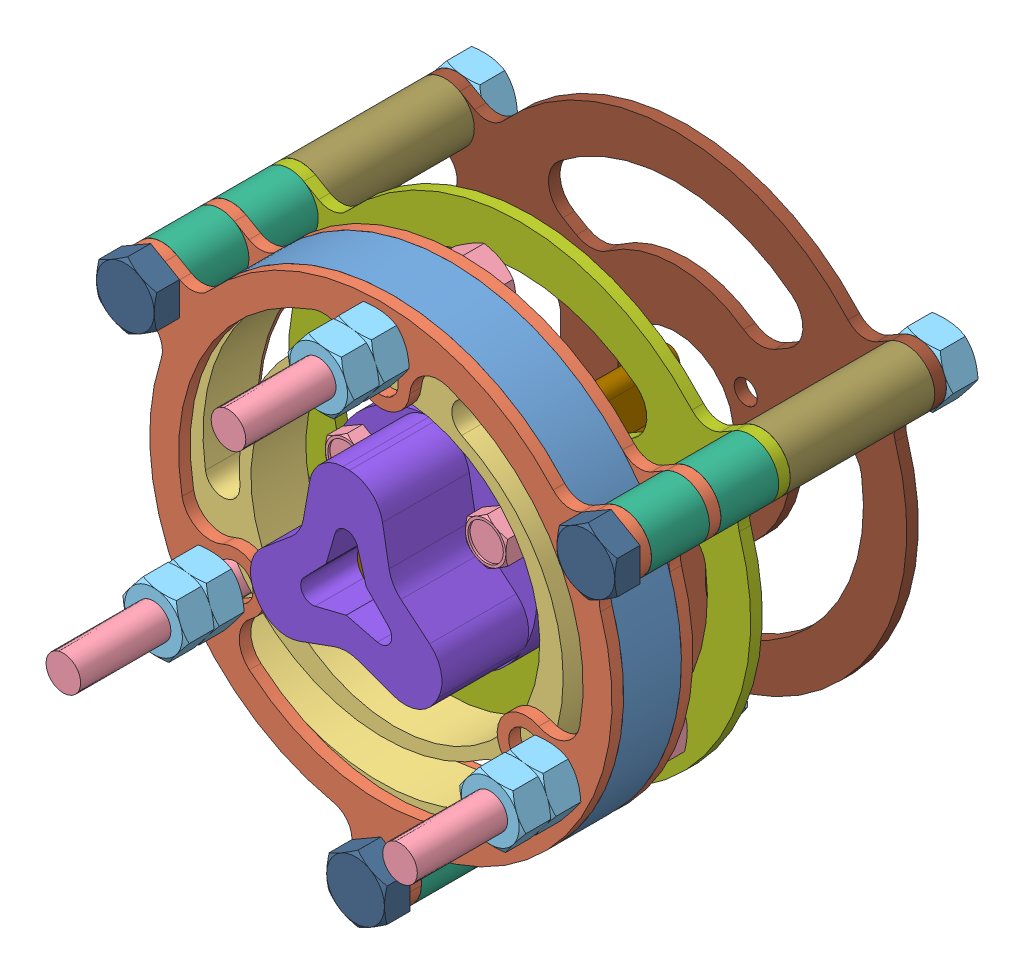
SolidWorks assembly Tri-Claw-Claw, configuration Default. Lengths in mm.
Overall size (123.65 123.16 86).
39 component instances, 13 part files, 77 mates.
Components (placement in the parent):
- ClawHousing-1: ClawHousing [Default] x (0.805239 -0.592951 0) z (0 0 1) size (80 80 10)
- ClawFrame-1: ClawFrame [Default] at (0 0 -2) x (0.866025 -0.5 0) z (0 0 1) size (91 89.67 2)
- ClawFrame-2: ClawFrame [Default] at (0 0 10) x (0.866025 -0.5 0) z (0 0 1) size (91 89.67 2)
- ClawCam-1: ClawCam [Default] x (-0.82094 -0.571014 0) z (0 0 1) size (76 76 9.5)
- hex screw_am-1: hex screw_am [B18.6.7M - M6 x 1.0 x 40 Indented HHMS --40N] at (-0.3706 33.6346 -6.7) x (0 0 1) z (-1 0 0) size (44.7 11.55 10)
- hex screw_am-2: hex screw_am [B18.6.7M - M6 x 1.0 x 40 Indented HHMS --40N] at (29.3137 -16.4964 -6.7) x (0 0 1) z (-1 0 0) size (44.7 11.55 10)
- hex screw_am-3: hex screw_am [B18.6.7M - M6 x 1.0 x 40 Indented HHMS --40N] at (-28.9431 -17.1383 -6.7) x (0 0 1) z (-1 0 0) size (44.7 11.55 10)
- hex nut style 1_am-1: hex nut style 1_am [B18.2.4.1M - Hex nut, Style 1,  M6 x 1 --D-N] at (-0.3706 33.6346 17.2) x (-0.923728 -0.383049 0) z (0 0 -1) size (10 11.55 5.2)
- hex nut style 1_am-2: hex nut style 1_am [B18.2.4.1M - Hex nut, Style 1,  M6 x 1 --D-N] at (29.3137 -16.4964 17.2) x (-0.923728 -0.383049 0) z (0 0 -1) size (10 11.55 5.2)
- hex nut style 1_am-3: hex nut style 1_am [B18.2.4.1M - Hex nut, Style 1,  M6 x 1 --D-N] at (-28.9431 -17.1383 17.2) x (-0.923728 -0.383049 0) z (0 0 -1) size (10 11.55 5.2)
- hex nut style 1_am-4: hex nut style 1_am [B18.2.4.1M - Hex nut, Style 1,  M6 x 1 --D-N] at (-0.3706 33.6346 12) x (-0.923728 -0.383049 0) z (0 0 -1) size (10 11.55 5.2)
- hex nut style 1_am-5: hex nut style 1_am [B18.2.4.1M - Hex nut, Style 1,  M6 x 1 --D-N] at (29.3137 -16.4964 12) x (-0.923728 -0.383049 0) z (0 0 -1) size (10 11.55 5.2)
- hex nut style 1_am-6: hex nut style 1_am [B18.2.4.1M - Hex nut, Style 1,  M6 x 1 --D-N] at (-28.9431 -17.1383 12) x (-0.923728 -0.383049 0) z (0 0 -1) size (10 11.55 5.2)
- ClawSpacer-1: ClawSpacer [Default] at (-39.8372 23 -2) x (-1 0 0) z (0 0 -1) size (10 10 10)
- ClawSpacer-2: ClawSpacer [Default] at (39.8372 23 -2) x (-1 0 0) z (0 0 -1) size (10 10 10)
- ClawSpacer-3: ClawSpacer [Default] at (0 -46 -2) x (-1 0 0) z (0 0 -1) size (10 10 10)
- ClawBackFrame-1: ClawBackFrame [Default] at (0 0 -14) x (0.866025 -0.5 0) z (0 0 1) size (91 89.67 2)
- Plate-TriStar-1: Plate-TriStar [Default] at (0 0 22.4) x (0.999374 -0.035386 0) z (0 0 1) size (60 60 1.5) (hidden)
- AlignmentToolHousing-1: AlignmentToolHousing [Default] at (0 0 -12) size (36 36 30)
- AlignmentTool-1: AlignmentTool [Default] at (0 0 12.2777) x (-1 0 0) z (0 0 -1) size (15.93 15.31 50)
- hex screw_am-4: hex screw_am [B18.6.7M - M4 x 0.7 x 25 Indented HHMS --25N] at (12.1244 7 6) x (0 0 -1) z (1 0 0) size (28 8.08 7)
- hex screw_am-5: hex screw_am [B18.6.7M - M4 x 0.7 x 25 Indented HHMS --25N] at (-12.1244 7 6) x (0 0 -1) z (1 0 0) size (28 8.08 7)
- hex screw_am-6: hex screw_am [B18.6.7M - M4 x 0.7 x 25 Indented HHMS --25N] at (0 -14 6) x (0 0 -1) z (1 0 0) size (28 8.08 7)
- ClawSpacer-4: ClawSpacer [Default] at (-39.8372 23 10) x (-1 0 0) z (0 0 -1) size (10 10 10)
- ClawSpacer-5: ClawSpacer [Default] at (39.8372 23 0) x (0.923728 0.383049 0) z (0 0 1) size (10 10 10)
- ClawSpacer-6: ClawSpacer [Default] at (0 -46 10) x (-1 0 0) z (0 0 -1) size (10 10 10)
- hex nut style 1_am-10: hex nut style 1_am [B18.2.4.1M - Hex nut, Style 1,  M4 x 0.7 --D-N] at (-12.1244 7 -17.2) x (0.923728 0.383049 0) z (0 0 -1) size (7 8.08 3.2)
- hex nut style 1_am-11: hex nut style 1_am [B18.2.4.1M - Hex nut, Style 1,  M4 x 0.7 --D-N] at (12.1244 7 -17.2) x (0.923728 0.383049 0) z (0 0 -1) size (7 8.08 3.2)
- hex nut style 1_am-12: hex nut style 1_am [B18.2.4.1M - Hex nut, Style 1,  M4 x 0.7 --D-N] at (0 -14 -17.2) x (0.925899 0.377771 0) z (0 0 -1) size (7 8.08 3.2)
- hex bolt_am-1: hex bolt_am [B18.2.3.5M - Hex bolt M6 x 1.0 x 60 --18N] at (39.8372 23 16.38) x (0 0 -1) z (1 0 0) size (64.38 11.55 10)
- hex bolt_am-2: hex bolt_am [B18.2.3.5M - Hex bolt M6 x 1.0 x 60 --18N] at (0 -46 16.38) x (0 0 -1) z (1 0 0) size (64.38 11.55 10)
- hex bolt_am-3: hex bolt_am [B18.2.3.5M - Hex bolt M6 x 1.0 x 60 --18N] at (-39.8372 23 16.38) x (0 0 -1) z (1 0 0) size (64.38 11.55 10)
- ClawBackFrameMount-1: ClawBackFrameMount [Default] at (0 0 -41) x (0.866025 -0.5 0) z (0 0 1) size (91 89.67 2)
- ClawSpacerLong-1: ClawSpacerLong [Default] at (-39.8372 23 -14) x (-1 0 0) z (0 0 -1) size (10 10 25)
- ClawSpacerLong-2: ClawSpacerLong [Default] at (0 -46 -14) x (-1 0 0) z (0 0 -1) size (10 10 25)
- ClawSpacerLong-3: ClawSpacerLong [Default] at (39.8372 23 -14) x (-1 0 0) z (0 0 -1) size (10 10 25)
- hex nut style 1_am-13: hex nut style 1_am [B18.2.4.1M - Hex nut, Style 1,  M6 x 1 --D-N] at (0 -46 -46.2) x (0.923728 0.383049 0) z (0 0 -1) size (10 11.55 5.2)
- hex nut style 1_am-14: hex nut style 1_am [B18.2.4.1M - Hex nut, Style 1,  M6 x 1 --D-N] at (39.8372 23 -46.2) x (0.923728 0.383049 0) z (0 0 -1) size (10 11.55 5.2)
- hex nut style 1_am-15: hex nut style 1_am [B18.2.4.1M - Hex nut, Style 1,  M6 x 1 --D-N] at (-39.8372 23 -46.2) x (0.923728 0.383049 0) z (0 0 -1) size (10 11.55 5.2)
Mates (geometry in assembly coordinates):
- Coincident1: coincident: plane of ClawHousing-1 through (0 0 0) normal (0 0 -1); plane of ClawFrame-1 through (0 0 0) normal (0 0 1)
- Concentric1: concentric: cylinder of ClawHousing-1 through (0 0 10) axis (0 0 -1) radius 40; cylinder of ClawFrame-1 through (0 0 0) axis (0 0 -1) radius 40
- Concentric2: concentric: cylinder of ClawHousing-1 through (0 0 10) axis (0 0 -1) radius 40; cylinder of ClawFrame-2 through (0 0 12) axis (0 0 -1) radius 40
- Coincident2: coincident: plane of ClawHousing-1 through (0 0 10) normal (0 0 1); plane of ClawFrame-2 through (0 0 10) normal (0 0 -1)
- Concentric4: concentric: cylinder of ClawHousing-1 through (0 0 10) axis (0 0 -1) radius 40; cylinder of ClawCam-1 through (0 0 9.5) axis (0 0 -1) radius 38
- Concentric25: concentric: cylinder of ClawHousing-1 through (0 0 10) axis (0 0 -1) radius 40; cylinder of Plate-TriStar-1 through (0 0 23.9) axis (0 0 -1) radius 30
- Concentric3: concentric: cylinder of ClawFrame-1 through (25.1147 -14.5 0) axis (0 0 -1) radius 3; cylinder of ClawFrame-2 through (25.1147 -14.5 12) axis (0 0 -1) radius 3
- Coincident7: coincident: plane of ClawFrame-1 through (0 0 0) normal (0 0 1); plane of ClawCam-1 through (0 0 0) normal (0 0 -1)
- Concentric20: concentric: cylinder of ClawFrame-1 through (-39.8372 23 0) axis (0 0 -1) radius 3; cylinder of ClawSpacer-1 through (-39.8372 23 -12) axis (0 0 1) radius 3
- Coincident19: coincident: plane of ClawFrame-1 through (0 0 -2) normal (0 0 -1); plane of ClawSpacer-1 through (-39.8372 23 -2) normal (0 0 1)
- Concentric21: concentric: cylinder of ClawFrame-1 through (39.8372 23 0) axis (0 0 -1) radius 3; cylinder of ClawSpacer-2 through (39.8372 23 -12) axis (0 0 1) radius 3
- Coincident20: coincident: plane of ClawFrame-1 through (0 0 -2) normal (0 0 -1); plane of ClawSpacer-2 through (39.8372 23 -2) normal (0 0 1)
- Concentric22: concentric: cylinder of ClawFrame-1 through (0 -46 0) axis (0 0 -1) radius 3; cylinder of ClawSpacer-3 through (0 -46 -12) axis (0 0 1) radius 3
- Coincident21: coincident: plane of ClawFrame-1 through (0 0 -2) normal (0 0 -1); plane of ClawSpacer-3 through (0 -46 -2) normal (0 0 1)
- Concentric37: concentric: cylinder of ClawFrame-1 through (-39.8372 23 0) axis (0 0 -1) radius 3; cylinder of ClawSpacer-4 through (-39.8372 23 0) axis (0 0 1) radius 3
- Coincident33: coincident: plane of ClawFrame-1 through (0 0 0) normal (0 0 1); plane of ClawSpacer-5 through (39.8372 23 0) normal (0 0 -1)
- Coincident13: coincident: plane of ClawFrame-2 through (0 0 12) normal (0 0 1); plane of hex nut style 1_am-4 through (-2.5821 38.9678 12) normal (0 0 -1)
- Coincident15: coincident: plane of ClawFrame-2 through (0 0 12) normal (0 0 1); plane of hex nut style 1_am-5 through (27.1022 -11.1632 12) normal (0 0 -1)
- Coincident17: coincident: plane of ClawFrame-2 through (0 0 12) normal (0 0 1); plane of hex nut style 1_am-6 through (-31.1547 -11.8051 12) normal (0 0 -1)
- Coincident32: coincident: plane of ClawFrame-2 through (0 0 10) normal (0 0 -1); plane of ClawSpacer-4 through (-39.8372 23 10) normal (0 0 1)
- Concentric39: concentric: cylinder of ClawFrame-2 through (39.8372 23 12) axis (0 0 -1) radius 3; cylinder of ClawSpacer-5 through (39.8372 23 10) axis (0 0 -1) radius 3
- Coincident34: coincident: plane of ClawFrame-2 through (0 0 10) normal (0 0 -1); plane of ClawSpacer-6 through (0 -46 10) normal (0 0 1)
- Concentric40: concentric: cylinder of ClawFrame-2 through (0 -46 12) axis (0 0 -1) radius 3; cylinder of ClawSpacer-6 through (0 -46 0) axis (0 0 1) radius 3
- CamMateTangent2: cam tangent: cylinder of ClawCam-1 through (3.5524 0.2996 9.5) axis (0 0 -1) radius 30.5651; cylinder of hex screw_am-1 through (-0.3706 33.6346 -32.1) axis (0 0 -1) radius 3
- CamMateTangent3: cam tangent: cylinder of ClawCam-1 through (-2.0357 2.9267 9.5) axis (0 0 -1) radius 30.5651; cylinder of hex screw_am-3 through (-28.9431 -17.1383 -32.1) axis (0 0 -1) radius 3
- CamMateTangent4: cam tangent: cylinder of ClawCam-1 through (-1.5167 -3.2263 9.5) axis (0 0 -1) radius 30.5651; cylinder of hex screw_am-2 through (29.3137 -16.4964 -32.1) axis (0 0 -1) radius 3
- Concentric12: concentric: cylinder of hex screw_am-1 through (-0.3706 33.6346 -32.1) axis (0 0 -1) radius 3; cylinder of hex nut style 1_am-1 through (-0.3706 33.6346 42.2375) axis (0 0 -1) radius 3
- Concentric15: concentric: cylinder of hex screw_am-1 through (-0.3706 33.6346 -32.1) axis (0 0 -1) radius 3; cylinder of hex nut style 1_am-4 through (-0.3706 33.6346 37.0375) axis (0 0 -1) radius 3
- Concentric13: concentric: cylinder of hex screw_am-2 through (29.3137 -16.4964 -32.1) axis (0 0 -1) radius 3; cylinder of hex nut style 1_am-2 through (29.3137 -16.4964 42.2375) axis (0 0 -1) radius 3
- Concentric16: concentric: cylinder of hex screw_am-2 through (29.3137 -16.4964 -32.1) axis (0 0 -1) radius 3; cylinder of hex nut style 1_am-5 through (29.3137 -16.4964 37.0375) axis (0 0 -1) radius 3
- Concentric14: concentric: cylinder of hex screw_am-3 through (-28.9431 -17.1383 -32.1) axis (0 0 -1) radius 3; cylinder of hex nut style 1_am-3 through (-28.9431 -17.1383 42.2375) axis (0 0 -1) radius 3
- Concentric17: concentric: cylinder of hex screw_am-3 through (-28.9431 -17.1383 -32.1) axis (0 0 -1) radius 3; cylinder of hex nut style 1_am-6 through (-28.9431 -17.1383 37.0375) axis (0 0 -1) radius 3
- Coincident14: coincident: plane of hex nut style 1_am-1 through (-2.5821 38.9678 17.2) normal (0 0 -1); plane of hex nut style 1_am-4 through (-2.5821 38.9678 17.2) normal (0 0 1)
- Coincident23: coincident: plane of hex nut style 1_am-1 through (-2.5821 38.9678 22.4) normal (0 0 1); plane of Plate-TriStar-1 through (0 0 22.4) normal (0 0 -1)
- Coincident16: coincident: plane of hex nut style 1_am-2 through (27.1022 -11.1632 17.2) normal (0 0 -1); plane of hex nut style 1_am-5 through (27.1022 -11.1632 17.2) normal (0 0 1)
- Coincident18: coincident: plane of hex nut style 1_am-3 through (-31.1547 -11.8051 17.2) normal (0 0 -1); plane of hex nut style 1_am-6 through (-31.1547 -11.8051 17.2) normal (0 0 1)
- Concentric24: concentric: cylinder of ClawSpacer-1 through (-39.8372 23 -12) axis (0 0 1) radius 3; cylinder of ClawBackFrame-1 through (-39.8372 23 -12) axis (0 0 -1) radius 3
- Coincident22: coincident: plane of ClawSpacer-1 through (-39.8372 23 -12) normal (0 0 -1); plane of ClawBackFrame-1 through (0 0 -12) normal (0 0 1)
- Concentric23: concentric: cylinder of ClawSpacer-2 through (39.8372 23 -12) axis (0 0 1) radius 3; cylinder of ClawBackFrame-1 through (39.8372 23 -12) axis (0 0 -1) radius 3
- Coincident24: coincident: plane of ClawBackFrame-1 through (0 0 -12) normal (0 0 1); plane of AlignmentToolHousing-1 through (0 0 -12) normal (0 0 -1)
- Concentric26: concentric: cylinder of ClawBackFrame-1 through (-12.1244 7 -6) axis (0 0 -1) radius 2; cylinder of AlignmentToolHousing-1 through (-12.1244 7 28) axis (0 0 -1) radius 2
- Concentric27: concentric: cylinder of ClawBackFrame-1 through (0 -14 -6) axis (0 0 -1) radius 2; cylinder of AlignmentToolHousing-1 through (0 -14 28) axis (0 0 -1) radius 2
- Coincident42: coincident: plane of ClawBackFrame-1 through (0 0 -14) normal (0 0 -1); plane of hex nut style 1_am-10 through (-10.5763 3.2668 -14) normal (0 0 1)
- Coincident43: coincident: plane of ClawBackFrame-1 through (0 0 -14) normal (0 0 -1); plane of hex nut style 1_am-11 through (13.6724 3.2668 -14) normal (0 0 1)
- Coincident44: coincident: plane of ClawBackFrame-1 through (0 0 -14) normal (0 0 -1); plane of hex nut style 1_am-12 through (1.5267 -17.742 -14) normal (0 0 1)
- Concentric28: concentric: cylinder of AlignmentToolHousing-1 through (0 6.7889 -12) axis (0 0 -1) radius 2; cylinder of AlignmentTool-1 through (0 6.7889 -37.7223) axis (0 0 1) radius 2
- Concentric29: concentric: cylinder of AlignmentToolHousing-1 through (5.8794 -3.3944 -12) axis (0 0 1) radius 2; cylinder of AlignmentTool-1 through (5.8794 -3.3944 -37.7223) axis (0 0 -1) radius 2
- Concentric31: concentric: cylinder of AlignmentToolHousing-1 through (12.1244 7 28) axis (0 0 -1) radius 2; cylinder of hex screw_am-4 through (12.1244 7 31.4) axis (0 0 1) radius 2
- Coincident26: coincident: plane of AlignmentToolHousing-1 through (0 0 3) normal (0 0 1); plane of hex screw_am-4 through (12.1244 9 3) normal (0 0 -1)
- Concentric32: concentric: cylinder of AlignmentToolHousing-1 through (-12.1244 7 28) axis (0 0 -1) radius 2; cylinder of hex screw_am-5 through (-12.1244 7 31.4) axis (0 0 1) radius 2
- Coincident27: coincident: plane of AlignmentToolHousing-1 through (0 0 3) normal (0 0 1); plane of hex screw_am-5 through (-12.1244 9 3) normal (0 0 -1)
- Concentric33: concentric: cylinder of AlignmentToolHousing-1 through (0 -14 28) axis (0 0 -1) radius 2; cylinder of hex screw_am-6 through (0 -14 31.4) axis (0 0 1) radius 2
- Coincident28: coincident: plane of AlignmentToolHousing-1 through (0 0 3) normal (0 0 1); plane of hex screw_am-6 through (0 -12 3) normal (0 0 -1)
- Concentric49: concentric: cylinder of hex screw_am-4 through (12.1244 7 31.4) axis (0 0 1) radius 2; cylinder of hex nut style 1_am-11 through (12.1244 7 7.8375) axis (0 0 -1) radius 2
- Concentric48: concentric: cylinder of hex screw_am-5 through (-12.1244 7 31.4) axis (0 0 1) radius 2; cylinder of hex nut style 1_am-10 through (-12.1244 7 7.8375) axis (0 0 -1) radius 2
- Concentric50: concentric: cylinder of hex screw_am-6 through (0 -14 31.4) axis (0 0 1) radius 2; cylinder of hex nut style 1_am-12 through (0 -14 7.8375) axis (0 0 -1) radius 2
- Concentric51: concentric: cylinder of ClawFrame-2 through (39.8372 23 12) axis (0 0 -1) radius 3; cylinder of hex bolt_am-1 through (39.8372 23 16.38) axis (0 0 1) radius 3
- Coincident47: coincident: plane of ClawFrame-2 through (0 0 12) normal (0 0 1); plane of hex bolt_am-1 through (39.8372 28.7735 12) normal (0 0 -1)
- Concentric52: concentric: cylinder of ClawFrame-2 through (0 -46 12) axis (0 0 -1) radius 5; cylinder of hex bolt_am-2 through (0 -46 16.38) axis (0 0 1) radius 3
- Coincident48: coincident: plane of ClawFrame-2 through (0 0 12) normal (0 0 1); plane of hex bolt_am-2 through (0 -40.2265 12) normal (0 0 -1)
- Concentric53: concentric: cylinder of ClawFrame-2 through (-39.8372 23 12) axis (0 0 -1) radius 3; cylinder of hex bolt_am-3 through (-39.8372 23 16.38) axis (0 0 1) radius 3
- Coincident49: coincident: plane of ClawFrame-2 through (0 0 12) normal (0 0 1); plane of hex bolt_am-3 through (-39.8372 28.7735 12) normal (0 0 -1)
- Concentric55: concentric: cylinder of ClawBackFrame-1 through (0 0 -12) axis (0 0 -1) radius 40; cylinder of ClawBackFrameMount-1 through (0 0 -39) axis (0 0 -1) radius 40
- Concentric56: concentric: circle of ClawBackFrame-1; circle of ClawBackFrameMount-1
- Coincident52: coincident: plane of ClawBackFrame-1 through (0 0 -14) normal (0 0 -1); plane of ClawSpacerLong-1 through (-39.8372 23 -14) normal (0 0 1)
- Coincident53: coincident: circle of ClawBackFrame-1; cylinder of ClawSpacerLong-1 through (-39.8372 23 -39) axis (0 0 1) radius 3
- Coincident54: coincident: plane of ClawBackFrameMount-1 through (0 0 -39) normal (0 0 1); plane of ClawSpacerLong-1 through (-39.8372 23 -39) normal (0 0 -1)
- Coincident55: coincident: circle of ClawBackFrameMount-1; cylinder of ClawSpacerLong-3 through (39.8372 23 -39) axis (0 0 1) radius 3
- Coincident56: coincident: plane of ClawBackFrame-1 through (0 0 -14) normal (0 0 -1); plane of ClawSpacerLong-3 through (39.8372 23 -14) normal (0 0 1)
- Concentric57: concentric: cylinder of hex bolt_am-2 through (0 -46 16.38) axis (0 0 1) radius 3; cylinder of ClawSpacerLong-2 through (0 -46 -39) axis (0 0 1) radius 3
- Coincident57: coincident: plane of ClawBackFrameMount-1 through (0 0 -39) normal (0 0 1); plane of ClawSpacerLong-2 through (0 -46 -39) normal (0 0 -1)
- Concentric58: concentric: cylinder of hex bolt_am-2 through (0 -46 16.38) axis (0 0 1) radius 3; cylinder of hex nut style 1_am-13 through (0 -46 -21.1625) axis (0 0 -1) radius 3
- Coincident58: coincident: plane of ClawBackFrameMount-1 through (0 0 -41) normal (0 0 -1); plane of hex nut style 1_am-13 through (2.2115 -51.3331 -41) normal (0 0 1)
- Concentric59: concentric: cylinder of hex bolt_am-1 through (39.8372 23 16.38) axis (0 0 1) radius 3; cylinder of hex nut style 1_am-14 through (39.8372 23 -21.1625) axis (0 0 -1) radius 3
- Coincident59: coincident: plane of ClawBackFrameMount-1 through (0 0 -41) normal (0 0 -1); plane of hex nut style 1_am-14 through (42.0487 17.6669 -41) normal (0 0 1)
- Concentric60: concentric: cylinder of hex bolt_am-3 through (-39.8372 23 16.38) axis (0 0 1) radius 3; cylinder of hex nut style 1_am-15 through (-39.8372 23 -21.1625) axis (0 0 -1) radius 3
- Coincident60: coincident: plane of ClawBackFrameMount-1 through (0 0 -41) normal (0 0 -1); plane of hex nut style 1_am-15 through (-37.6256 17.6669 -41) normal (0 0 1)
